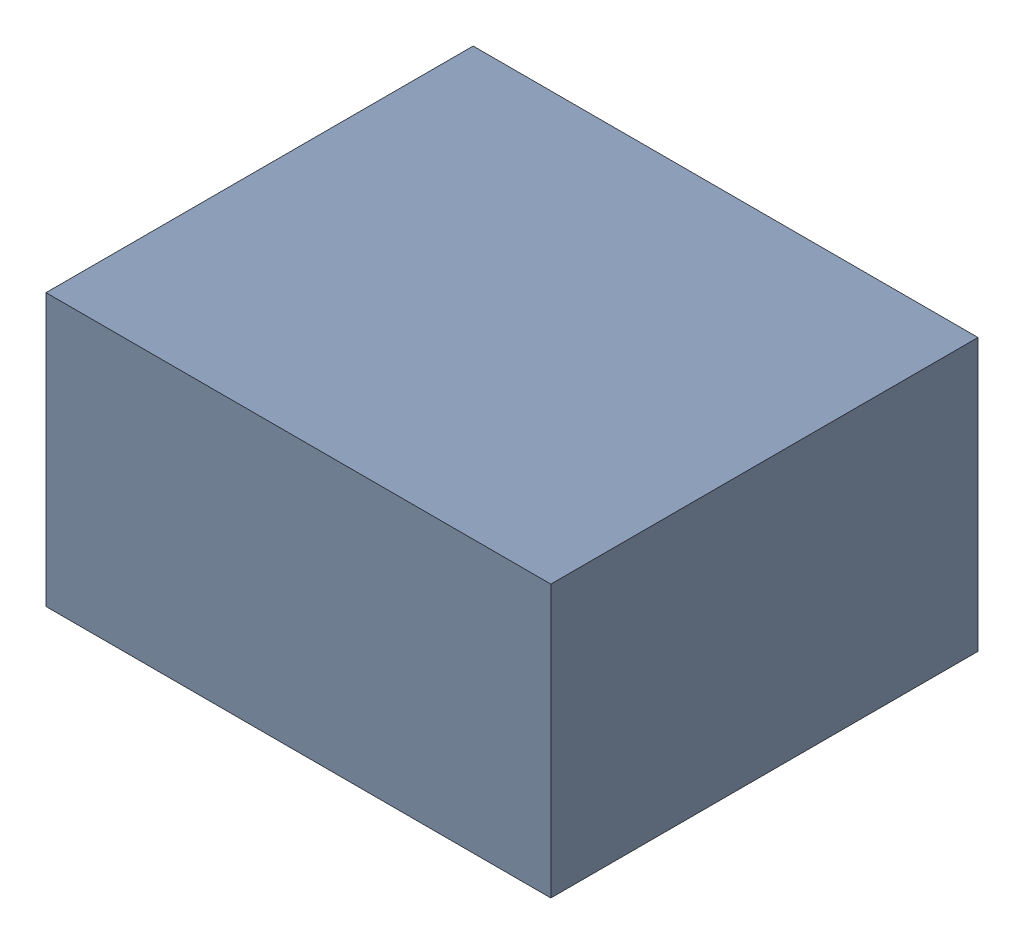
SolidWorks assembly L200, configuration Standard. Lengths in mm.
Overall size (0.65 0.35 0.55).
2 component instances, 1 part files, 0 mates.
Components (placement in the parent):
- 885541696-1: 885541696 [Standard] at (10.1 -24.75 0) size (0.65 0.35 0.55)
  - Extruded_32-1: Extruded_32 [Standard] at origin size (0.65 0.35 0.55)
